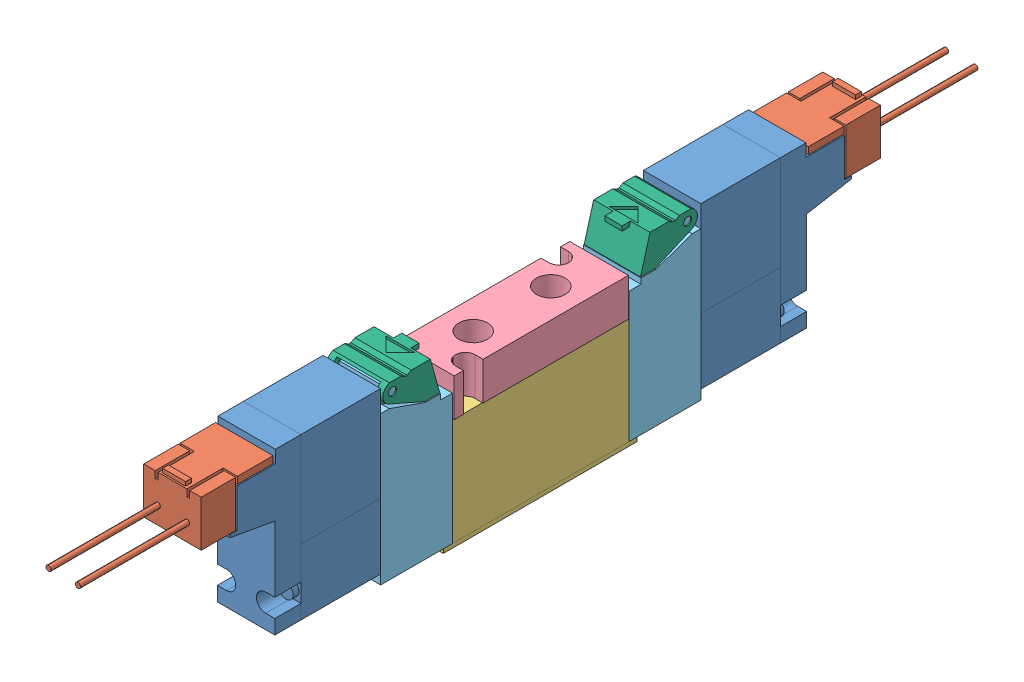
SolidWorks assembly 4GA129-M5-E01-4, configuration Default. Lengths in mm.
Overall size (10.2 30.4 156.1).
12 component instances, 6 part files, 0 mates.
Components (placement in the parent):
- 4GA129-M5-E01-4_D_100000_4G-Coil-SubASSY_01(EDC-E-H)-1: 4GA129-M5-E01-4_D_100000_4G-Coil-SubASSY_01(EDC-E-H) [Default] at (0 2.46 -27.85) size (10 27.94 50.2)
  - 4GA129-M5-E01-4_D_000102_4GcoilEDC_00(Default)-1: 4GA129-M5-E01-4_D_000102_4GcoilEDC_00(Default) [Default] at origin size (10 27.94 26.2)
  - 4GA129-M5-E01-4_D_000123_4GSocketAssyE_00(Default)-1: 4GA129-M5-E01-4_D_000123_4GSocketAssyE_00(Default) [Default] at (0 22.17 -25.2) size (10 8.7 31.5)
- 4GA129-M5-E01-4_D_100000_4G-Coil-SubASSY_01(EDC-E-H)-1-1: 4GA129-M5-E01-4_D_100000_4G-Coil-SubASSY_01(EDC-E-H)-1 [Default] at (0 2.46 27.85) x (-1 0 0) z (0 0 -1) size (10 27.94 50.2)
  - 4GA129-M5-E01-4_D_000102_4GcoilEDC_00(Default)-1: 4GA129-M5-E01-4_D_000102_4GcoilEDC_00(Default) [Default] at origin size (10 27.94 26.2)
  - 4GA129-M5-E01-4_D_000123_4GSocketAssyE_00(Default)-1: 4GA129-M5-E01-4_D_000123_4GSocketAssyE_00(Default) [Default] at (0 22.17 -25.2) size (10 8.7 31.5)
- 4GA129-M5-E01-4_D_000091_4G1Body_00(Default)-1: 4GA129-M5-E01-4_D_000091_4G1Body_00(Default) [Default] at origin size (10 19.4 33.7)
- 4GA129-M5-E01-4_D_000100_4G1PlateM5_00(Default)-1: 4GA129-M5-E01-4_D_000100_4G1PlateM5_00(Default) [Default] at (0 19.4 0) size (10.2 6.6 30.3)
- 4GA129-M5-E01-4_D_000097_4G1PistonAssy_00(Default)-1: 4GA129-M5-E01-4_D_000097_4G1PistonAssy_00(Default) [Default] at (0 0.8 15.35) x (-1 0 0) z (0 0 -1) size (10 28.72 12.5)
- 4GA129-M5-E01-4_D_000097_4G1PistonAssy_00(Default)-2: 4GA129-M5-E01-4_D_000097_4G1PistonAssy_00(Default) [Default] at (0 0.8 -15.35) size (10 28.72 12.5)
- 4GA129-M5-E01-4_D_000094_4G1ManualCover_00(Default)-1: 4GA129-M5-E01-4_D_000094_4G1ManualCover_00(Default) [Default] at (0 28.8 25.65) x (-1 0 0) z (0 0 -1) size (9.8 5.9 9.89)
- 4GA129-M5-E01-4_D_000094_4G1ManualCover_00(Default)-2: 4GA129-M5-E01-4_D_000094_4G1ManualCover_00(Default) [Default] at (0 28.8 -25.65) size (9.8 5.9 9.89)
